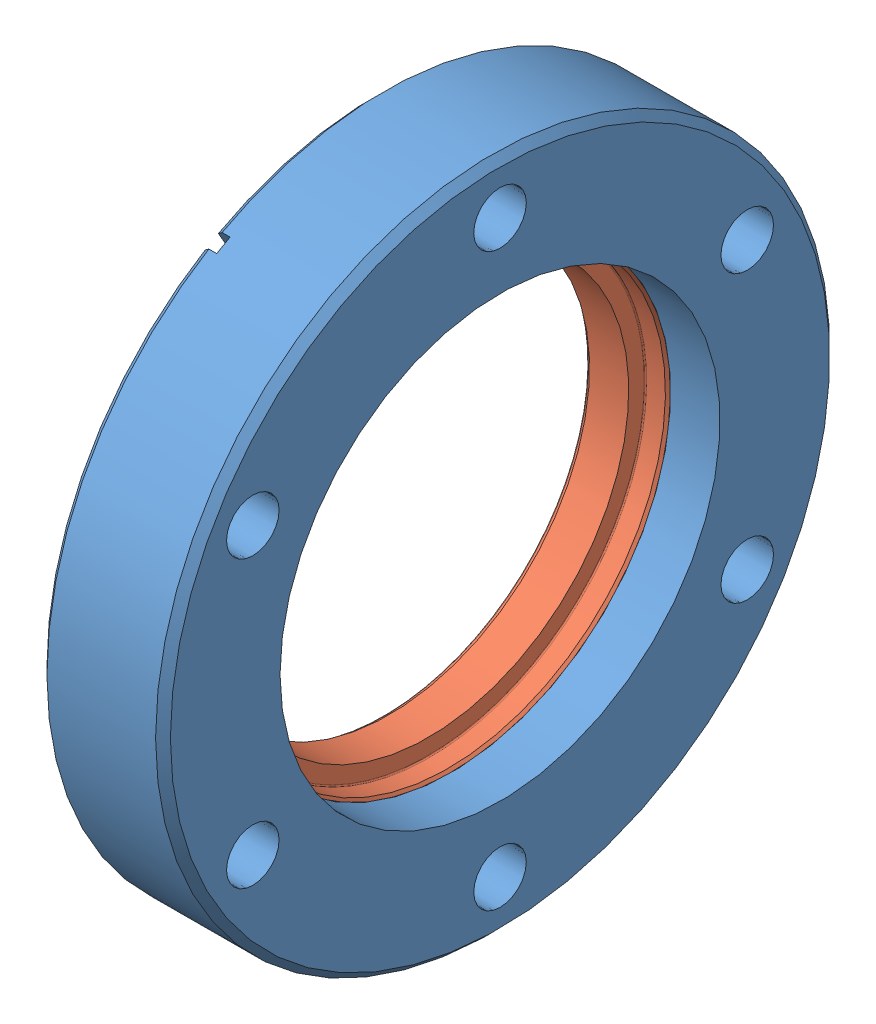
SolidWorks assembly 120093, configuration Default. Lengths in mm.
Overall size (12.71 69.34 69.34).
2 component instances, 2 part files, 2 mates.
Components (placement in the parent):
- 990365-1: 990365 [Default] at (14.8533 36.7932 55.2853) size (12.71 69.34 69.34)
- 990367-1: 990367 [Default] at (15.5137 36.7932 55.2853) x (1 0 0) z (0 0.021234 0.999775) size (6.91 48.06 48.06)
Mates (geometry in assembly coordinates):
- Concentric1: concentric aligned: cylinder of 990365-1 through (14.8533 36.7932 55.2853) axis (-1 0 0) radius 34.671; cylinder of 990367-1 through (15.5137 36.7932 55.2853) axis (-1 0 0) radius 24.0284
- Coincident1: coincident anti-aligned: plane of 990365-1 through (22.4733 60.9486 55.2853) normal (-1 0 0); plane of 990367-1 through (22.4733 59.1401 54.8106) normal (1 0 0)
